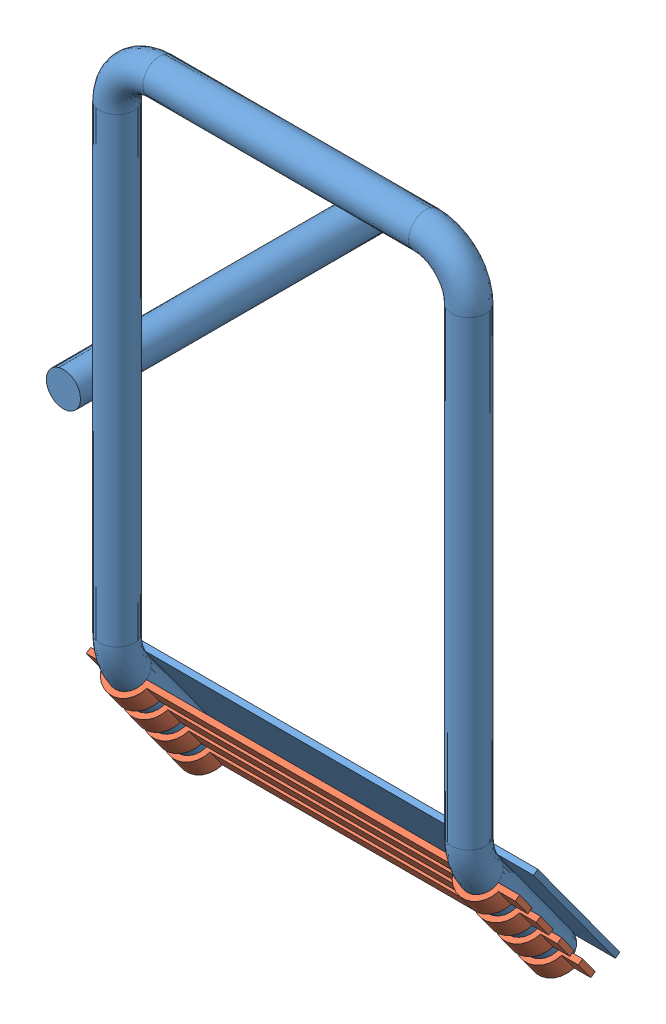
SolidWorks assembly 845 - BOAT ASSEMBLY, configuration Default. Lengths in mm.
Overall size (20.5 31.53 15).
2 component instances, 2 part files, 3 mates.
Components (placement in the parent):
- 845 - boat frame-1: 845 - boat frame [Default] at origin size (20.5 31.27 15)
- 845 - boat part 2-1: 845 - boat part 2 [Default] at (0 4.7402 20.4296) x (1 0 0) z (0 -0.809017 -0.587785) size (20 1.05 6)
Mates (geometry in assembly coordinates):
- Coincident1: coincident anti-aligned: plane of 845 - boat frame-1 through (-10 5.2104 19.7824) normal (0 0.809017 0.587785); plane of 845 - boat part 2-1 through (0 4.7402 20.4296) normal (0 -0.809017 -0.587785)
- Distance1: distance = 0.8 mm aligned: plane of 845 - boat part 2-1 through (0 4.7402 20.4296) normal (0 -0.587785 0.809017); plane of 845 - boat frame-1 through (-10 5.2104 19.7824) normal (0 -0.587785 0.809017)
- Coincident3: coincident aligned: plane of 845 - boat frame-1 through (0 0 0) normal (1 0 0); plane of 845 - boat part 2-1
